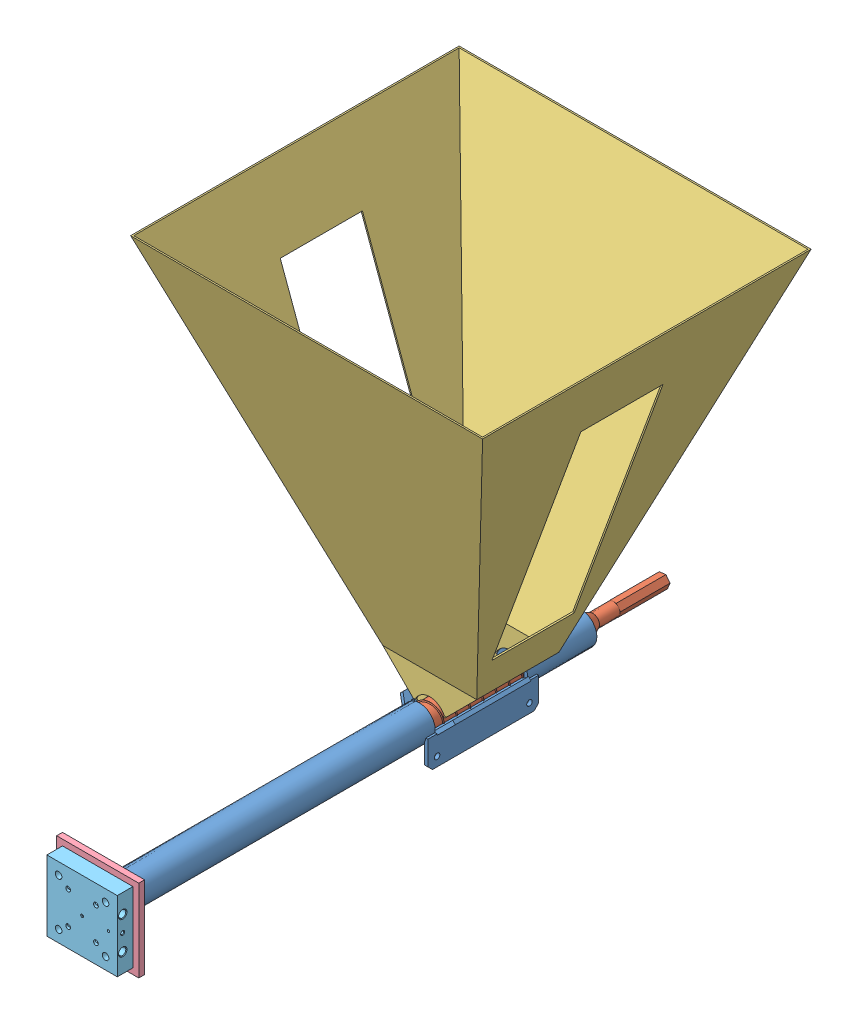
SolidWorks assembly Assem2, configuration Default. Lengths in mm.
Overall size (381 465.33 629.17).
5 component instances, 5 part files, 10 mates.
Components (placement in the parent):
- Barrel1.3-3: Barrel1.3 [Default] at (186.0939 -294.0427 -678.7466) x (1 0 0) z (0 0 -1) size (59.62 50.48 540)
- Screw-1: Screw [Default] at (186.0939 -294.0427 -767.6466) x (0.626807 -0.779175 0) z (-0.779175 -0.626807 0) size (28.19 600.01 28.62)
- Hopper-1: Hopper [Default] at (186.0939 -292.2647 -514.8466) size (381 416.97 355.6)
- flange-1: flange [Default] at (186.0939 -294.0427 -161.7466) size (88.9 88.9 6.83)
- Nozzle_3mm (1)-1: Nozzle_3mm (1) [Default] at (186.0939 -294.0427 -138.4816) x (0 -1 0) z (1 0 0) size (76.2 16.92 76.2)
Mates (geometry in assembly coordinates):
- Coincident1: coincident aligned: circle of Barrel1.3-3; circle of Screw-1
- Concentric1: concentric anti-aligned: cylinder of Barrel1.3-3 through (186.0939 -294.0427 -138.7466) axis (0 0 -1) radius 17; cylinder of Hopper-1 through (186.0939 -294.0427 -603.7466) axis (0 0 1) radius 17.272
- Parallel1: parallel aligned: plane of Barrel1.3-3 through (215.9043 -287.0835 -503.7466) normal (0.707107 -0.707107 0); plane of Hopper-1 through (198.7939 -292.2647 -516.4341) normal (0.707107 -0.707107 0)
- Coincident5: coincident anti-aligned: plane of Barrel1.3-3 through (203.0939 -277.0427 -603.7466) normal (0 0 1); plane of Hopper-1 through (186.0939 -292.2647 -603.7466) normal (0 0 -1)
- Concentric3: concentric anti-aligned: cylinder of Barrel1.3-3 through (186.0939 -294.0427 -161.7466) axis (0 0 1) radius 16; cylinder of flange-1 through (186.0939 -294.0427 -155.3966) axis (0 0 -1) radius 14.732
- Coincident6: coincident anti-aligned: plane of Barrel1.3-3 through (186.0939 -294.0427 -161.7466) normal (0 0 1); plane of flange-1 through (186.0939 -294.0427 -161.7466) normal (0 0 -1)
- Coincident8: coincident anti-aligned: plane of flange-1 through (186.0939 -294.0427 -155.3966) normal (0 0 1); plane of Nozzle_3mm (1)-1 through (186.0939 -294.0427 -155.3966) normal (0 0 -1)
- Parallel3: parallel anti-aligned: plane of Barrel1.3-3 through (186.0939 -294.0427 -138.7466) normal (0 0 1); plane of Nozzle_3mm (1)-1 through (186.0939 -283.2477 -149.0466) normal (0 0 -1)
- Concentric4: concentric anti-aligned: cylinder of Barrel1.3-3 through (186.0939 -294.0427 -161.7466) axis (0 0 1) radius 16; cylinder of Nozzle_3mm (1)-1 through (186.0939 -294.0427 -149.0466) axis (0 0 -1) radius 15.0495
- Parallel4: parallel aligned: plane of flange-1 through (141.6439 -338.4927 -155.3966) normal (-1 0 0); plane of Nozzle_3mm (1)-1 through (147.9939 -255.9427 -149.0466) normal (-1 0 0)
